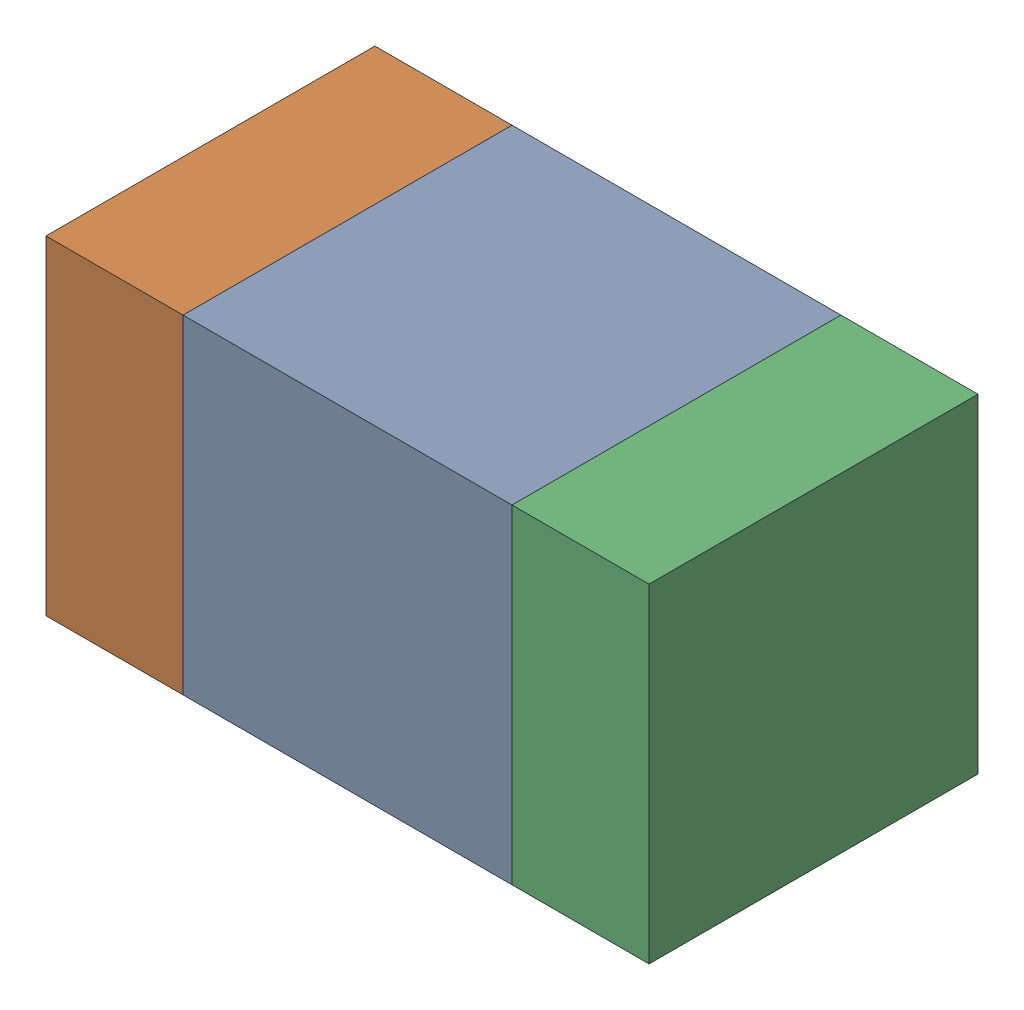
SolidWorks assembly C411PCB, configuration Default. Lengths in mm.
Overall size (1.1 0.6 0.6).
6 component instances, 2 part files, 0 mates.
Components (placement in the parent):
- 761606048-1: 761606048 [Default] at (87.69 89.1 0) size (0.6 0.6 0.6)
  - Extruded_9-1: Extruded_9 [Default] at origin size (0.6 0.6 0.6)
- 854785160-1: 854785160 [Default] at (87.265 89.1 0) size (0.25 0.6 0.6)
  - Extruded_19-1: Extruded_19 [Default] at origin size (0.25 0.6 0.6)
- 854785160-2: 854785160 [Default] at (88.115 89.1 0) size (0.25 0.6 0.6)
  - Extruded_19-1: Extruded_19 [Default] at origin size (0.25 0.6 0.6)
